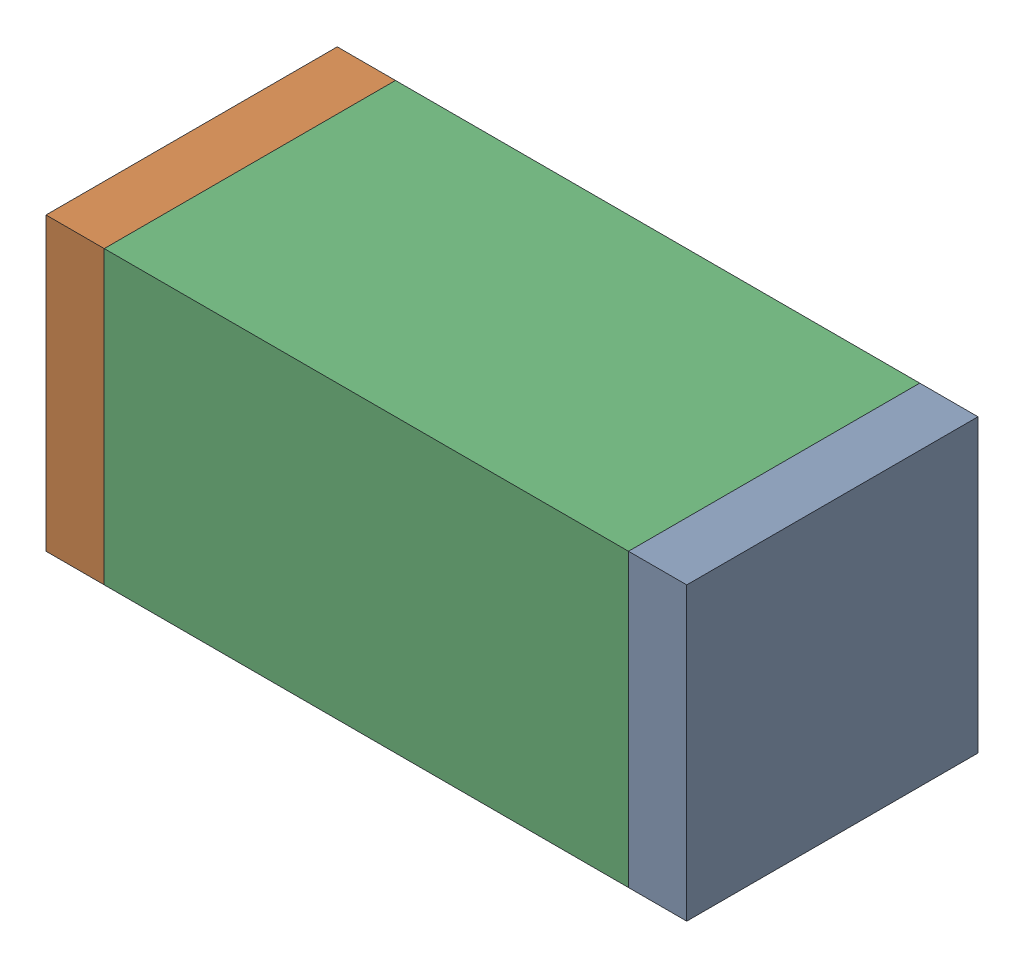
SolidWorks assembly C130, configuration Default. Lengths in mm.
Overall size (1.1 0.5 0.5).
6 component instances, 2 part files, 0 mates.
Components (placement in the parent):
- 810156080-1: 810156080 [Default] at (125.75 25.75 0) size (0.1 0.5 0.5)
  - Extruded_5-1: Extruded_5 [Default] at origin size (0.1 0.5 0.5)
- 810156080-2: 810156080 [Default] at (124.75 25.75 0) size (0.1 0.5 0.5)
  - Extruded_5-1: Extruded_5 [Default] at origin size (0.1 0.5 0.5)
- 836749680-1: 836749680 [Default] at (125.25 25.75 0) size (0.9 0.5 0.5)
  - Extruded_4-1: Extruded_4 [Default] at origin size (0.9 0.5 0.5)
